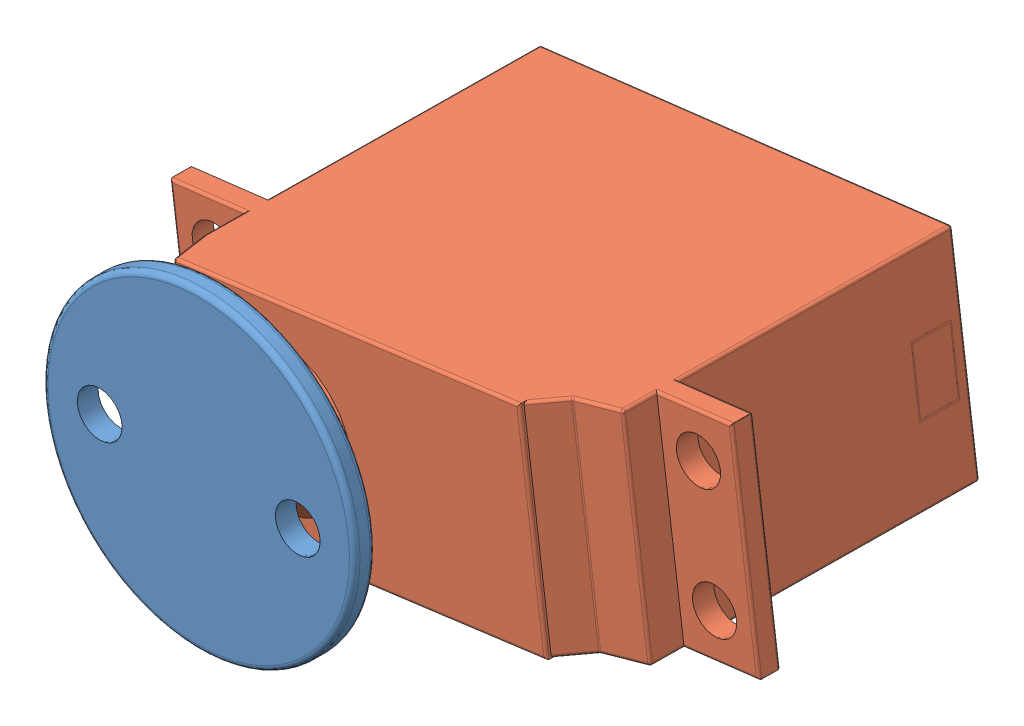
SolidWorks assembly ServoWithstickattach, configuration Default. Lengths in mm.
Overall size (57.96 30.11 43.26).
2 component instances, 2 part files, 2 mates.
Components (placement in the parent):
- servoAttachment-1: servoAttachment [Default] at (-60.2479 43.94 18.9537) size (30 30 4.5)
- servo motor-1: servo motor [Default] at (-28.0812 38.0219 6.8629) x (-0.99123 -0.131482 -0.013256) z (-0.131494 0.991317 0) size (55.24 41.08 20.19)
Mates (geometry in assembly coordinates):
- Concentric1: concentric aligned: cylinder of servoAttachment-1 through (-54.9229 46.2096 28.6088) axis (0 0 -1) radius 2.5; cylinder of servo motor-1 through (-54.9229 46.2096 28.6088) axis (0 0 -1) radius 2.921
- Coincident1: coincident anti-aligned: plane of servoAttachment-1 through (-54.9229 46.2096 28.6088) normal (0 0 -1); plane of servo motor-1 through (-16.795 51.2685 28.6088) normal (0 0 1)
